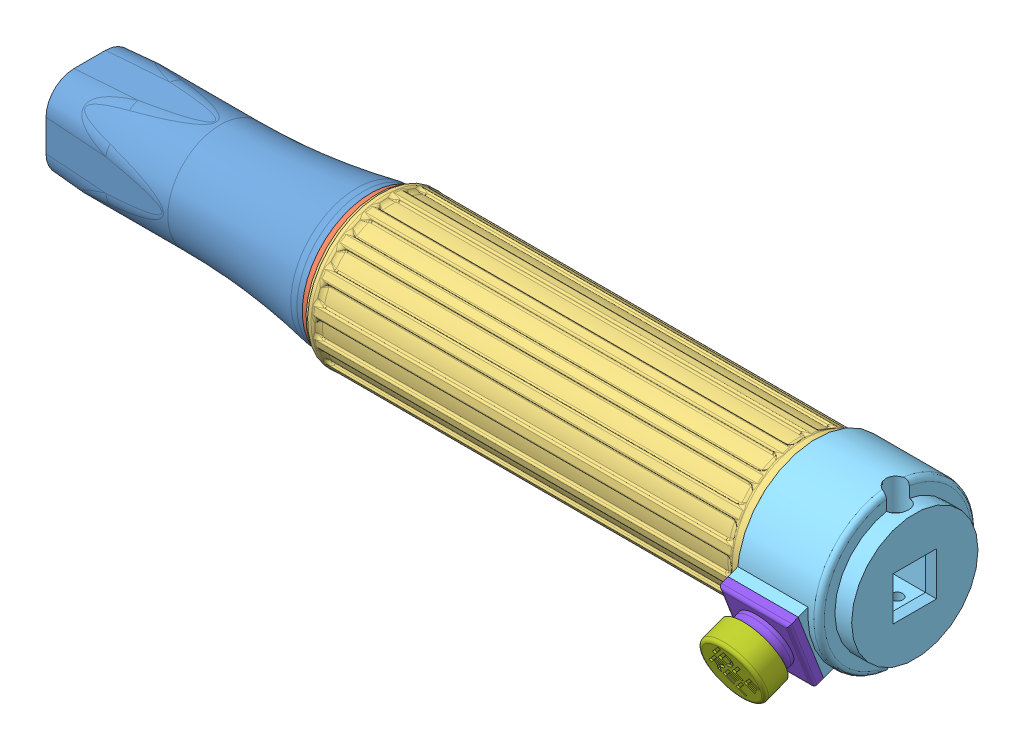
SolidWorks assembly slbe00_SingleCollectiveBodyEvo, configuration Default. Lengths in mm.
Overall size (235 50.81 64.17).
9 component instances, 9 part files, 21 mates.
Components (placement in the parent):
- slbe01_DecorativeCover-3: slbe01_DecorativeCover [По умолчанию] at (-40.1035 -80 -3.8534) x (0 0 -1) z (0 -1 0) size (38 80 38)
- slbe02_ThrottleFrameP1-1: slbe02_ThrottleFrameP1 [По умолчанию] at (96.8965 -80 -3.8534) x (0 1 0) z (0 0 1) size (39 77 39)
- slbe04_ThrottleGrip-1: slbe04_ThrottleGrip [По умолчанию] at (41.8965 -80 -3.8534) x (0 0.972648 0.232285) z (1 0 0) size (42.17 42.17 133.4)
- slbe03_ThrottleFrameP2-1: slbe03_ThrottleFrameP2 [По умолчанию] at (111.8965 -80 -3.8534) x (0 0 1) z (0 1 0) size (36 57 36)
- slbe05_ThrLatchHousingP1-1: slbe05_ThrLatchHousingP1 [По умолчанию] at (166.8965 -80 -3.8534) x (0 1 0) z (0 0 -1) size (45 28 47.7)
- slbe08_ThrLatchBtnP1-1: slbe08_ThrLatchBtnP1 [По умолчанию] at (176.8965 -90.4998 23.346) x (1 0 0) z (0 -0.932902 -0.36013) size (10 5 10)
- slbe09_ThrLatchBtnP2-1: slbe09_ThrLatchBtnP2 [По умолчанию] at (176.8965 -90.6799 23.8124) x (-0.764271 0.601624 0.232246) z (0.644895 0.71299 0.275237) size (18 7 18)
- slbe06_ThrLatchHousingP2-1: slbe06_ThrLatchHousingP2 [По умолчанию] at (176.8965 -88.339 17.7486) x (1 0 0) z (0 -0.932902 -0.36013) size (20 6 20)
- slbe07_ThrLatchPin-1: slbe07_ThrLatchPin [По умолчанию] at (176.8965 -91.2201 25.2118) x (0 -0.932902 -0.36013) z (1 0 0) size (9 18 7)
Mates (geometry in assembly coordinates):
- Parallel1: parallel anti-aligned: line of slbe01_DecorativeCover-3 through (37.149 -74.95 1.1966) axis (0 -1 0); line of slbe02_ThrottleFrameP1-1 through (42.6439 -85.05 1.1966) axis (0 1 0)
- Coincident7: coincident anti-aligned: plane of slbe01_DecorativeCover-3 through (39.8965 -80 -3.8534) normal (1 0 0); plane of slbe02_ThrottleFrameP1-1 through (39.8965 -80 -3.8534) normal (-1 0 0)
- Concentric1: concentric aligned: circle of slbe01_DecorativeCover-3; cylinder of slbe02_ThrottleFrameP1-1 through (39.8965 -80 -3.8534) axis (1 0 0) radius 19.5
- Concentric2: concentric anti-aligned: cylinder of slbe02_ThrottleFrameP1-1 through (41.8965 -80 -3.8534) axis (1 0 0) radius 18; cylinder of slbe04_ThrottleGrip-1 through (168.2965 -80 -3.8534) axis (-1 0 0) radius 18.3
- Concentric3: concentric anti-aligned: cylinder of slbe02_ThrottleFrameP1-1 through (41.8965 -80 -3.8534) axis (1 0 0) radius 18; cylinder of slbe03_ThrottleFrameP2-1 through (168.8965 -80 -3.8534) axis (-1 0 0) radius 18
- Coincident11: coincident aligned: plane of slbe02_ThrottleFrameP1-1 through (79.8965 -85.05 -8.9034) normal (0 0 1); plane of slbe03_ThrottleFrameP2-1 through (168.8965 -74.95 -8.9034) normal (0 0 1)
- Coincident12: coincident anti-aligned: plane of slbe02_ThrottleFrameP1-1 through (111.8965 -80 -3.8534) normal (1 0 0); plane of slbe03_ThrottleFrameP2-1 through (111.8965 -80 -3.8534) normal (-1 0 0)
- Coincident13: coincident anti-aligned: plane of slbe02_ThrottleFrameP1-1 through (41.8965 -80 -3.8534) normal (1 0 0); plane of slbe04_ThrottleGrip-1 through (41.8965 -80 -3.8534) normal (-1 0 0)
- Concentric4: concentric anti-aligned: circle of slbe03_ThrottleFrameP2-1; cylinder of slbe05_ThrLatchHousingP1-1 through (194.8965 -80 -3.8534) axis (-1 0 0) radius 22.5
- Parallel2: parallel aligned: plane of slbe03_ThrottleFrameP2-1 through (168.8965 -74.95 -8.9034) normal (0 0 1); plane of slbe05_ThrLatchHousingP1-1 through (194.8965 -74.95 -8.9034) normal (0 0 1)
- Coincident15: coincident anti-aligned: plane of slbe03_ThrottleFrameP2-1 through (168.8965 -80 -3.8534) normal (1 0 0); plane of slbe05_ThrLatchHousingP1-1 through (168.8965 -80 -3.8534) normal (-1 0 0)
- Concentric5: concentric anti-aligned: cylinder of slbe05_ThrLatchHousingP1-1 through (176.8965 -82.577 2.8221) axis (0 -0.36013 0.932902) radius 3.8; cylinder of slbe06_ThrLatchHousingP2-1 through (176.8965 -89.4194 20.5473) axis (0 0.36013 -0.932902) radius 3.8
- Coincident16: coincident anti-aligned: plane of slbe05_ThrLatchHousingP1-1 through (186.8965 -97.6681 14.1473) normal (0 -0.36013 0.932902); plane of slbe06_ThrLatchHousingP2-1 through (176.8965 -88.339 17.7486) normal (0 0.36013 -0.932902)
- Concentric6: concentric aligned: cylinder of slbe05_ThrLatchHousingP1-1 through (176.8965 -82.577 2.8221) axis (0 -0.36013 0.932902) radius 3.8; cylinder of slbe07_ThrLatchPin-1 through (176.8965 -84.7377 8.4195) axis (0 -0.36013 0.932902) radius 3.5
- Parallel3: parallel aligned: plane of slbe05_ThrLatchHousingP1-1 through (178.8965 -80 -3.8534) normal (-1 0 0); plane of slbe07_ThrLatchPin-1 through (175.8965 -92.5371 16.128) normal (-1 0 0)
- Coincident18: coincident anti-aligned: plane of slbe06_ThrLatchHousingP2-1 through (176.8965 -88.339 17.7486) normal (0 0.36013 -0.932902); plane of slbe07_ThrLatchPin-1 through (176.8965 -88.339 17.7486) normal (0 -0.36013 0.932902)
- Coincident19: coincident anti-aligned: plane of slbe08_ThrLatchBtnP1-1 through (176.8965 -91.2201 25.2118) normal (0 0.36013 -0.932902); plane of slbe07_ThrLatchPin-1 through (176.8965 -91.2201 25.2118) normal (0 -0.36013 0.932902)
- Concentric8: concentric anti-aligned: cylinder of slbe08_ThrLatchBtnP1-1 through (176.8965 -91.2201 25.2118) axis (0 0.36013 -0.932902) radius 3.7; cylinder of slbe07_ThrLatchPin-1 through (176.8965 -84.7377 8.4195) axis (0 -0.36013 0.932902) radius 3.5
- Coincident20: coincident anti-aligned: plane of slbe08_ThrLatchBtnP1-1 through (176.8965 -92.3005 28.0105) normal (0 -0.36013 0.932902); plane of slbe09_ThrLatchBtnP2-1 through (176.8965 -92.3005 28.0105) normal (0 0.36013 -0.932902)
- Concentric9: concentric aligned: cylinder of slbe08_ThrLatchBtnP1-1 through (176.8965 -92.3005 28.0105) axis (0 0.36013 -0.932902) radius 5; cylinder of slbe09_ThrLatchBtnP2-1 through (176.8965 -93.2008 30.3427) axis (0 0.36013 -0.932902) radius 9
- Coincident21: coincident aligned: plane of slbe05_ThrLatchHousingP1-1 through (186.8965 -96.5877 11.3486) normal (0 -0.932902 -0.36013); plane of slbe06_ThrLatchHousingP2-1 through (186.8965 -98.7484 16.946) normal (0 -0.932902 -0.36013)
